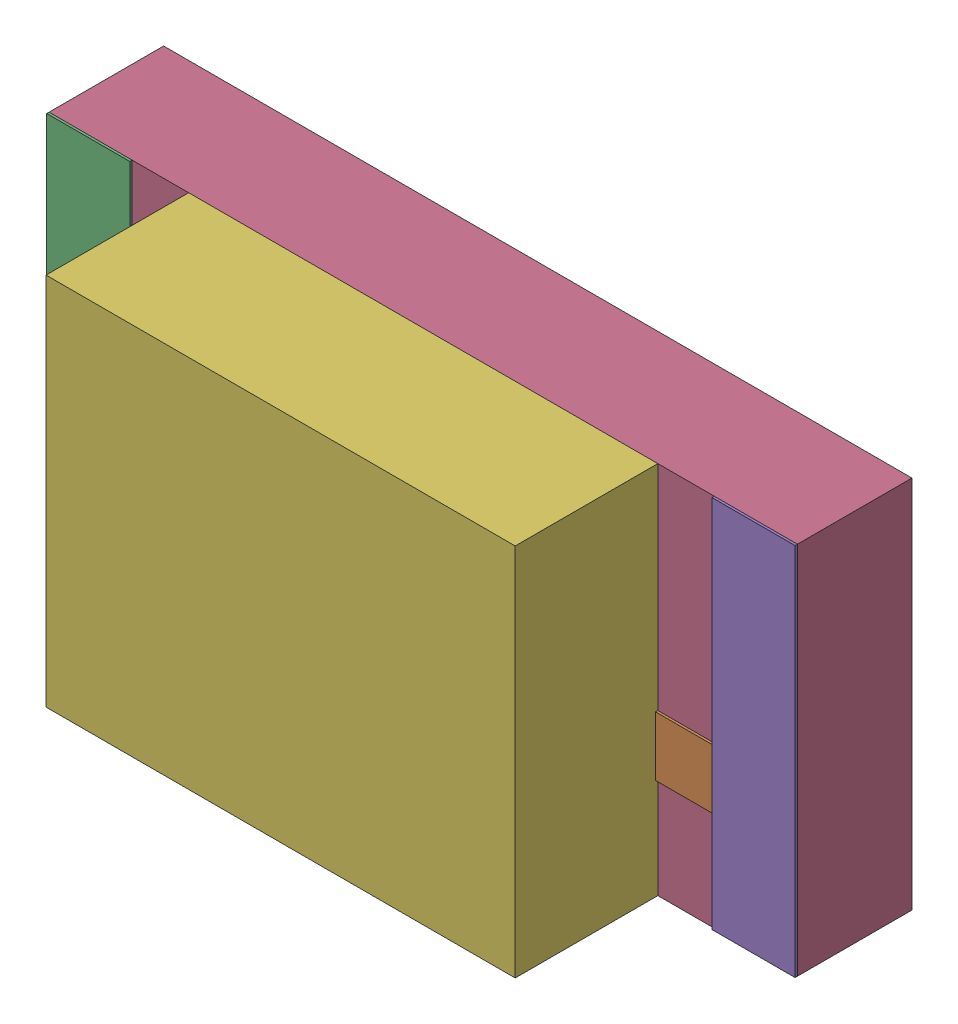
SolidWorks assembly SW3dPS-LED1206G, configuration Défaut. Lengths in mm.
Overall size (3.2 1.6 1.52).
14 component instances, 6 part files, 0 mates.
Components (placement in the parent):
- SW3dPS-LED1206G_Open_CASCADE_STEP_translator_6.2_262.2-1: SW3dPS-LED1206G_Open_CASCADE_STEP_translator_6.2_262.2 [Défaut] at origin size (3.2 1.6 1.1)
  - SW3dPS-LED1206G_352699472-1: SW3dPS-LED1206G_352699472 [Défaut] at (0.6096 0.0254 0.5027) size (0.65 0.76 0.01)
    - SW3dPS-LED1206G_Extruded-1: SW3dPS-LED1206G_Extruded [Défaut] at origin size (0.65 0.76 0.01)
  - SW3dPS-LED1206G_352698192-1: SW3dPS-LED1206G_352698192 [Défaut] at (2.1971 0.0254 0.5027) size (1.14 0.76 0.01)
    - SW3dPS-LED1206G_Extruded4-1: SW3dPS-LED1206G_Extruded4 [Défaut] at origin size (1.14 0.76 0.01)
  - SW3dPS-LED1206G_352697808-1: SW3dPS-LED1206G_352697808 [Défaut] at (0.1016 0.0127 0.5027) size (0.36 1.6 0.01)
    - SW3dPS-LED1206G_Extruded2-1: SW3dPS-LED1206G_Extruded2 [Défaut] at origin size (0.36 1.6 0.01)
  - SW3dPS-LED1206G_352697936-1: SW3dPS-LED1206G_352697936 [Défaut] at (1.524 0.0127 0.0127) size (3.2 1.6 0.49)
    - SW3dPS-LED1206G_Extruded1-1: SW3dPS-LED1206G_Extruded1 [Défaut] at origin size (3.2 1.6 0.49)
  - SW3dPS-LED1206G_352697808-2: SW3dPS-LED1206G_352697808 [Défaut] at (2.9464 0.0127 0.5027) size (0.36 1.6 0.01)
    - SW3dPS-LED1206G_Extruded2-1: SW3dPS-LED1206G_Extruded2 [Défaut] at origin size (0.36 1.6 0.01)
  - SW3dPS-LED1206G_352700880-1: SW3dPS-LED1206G_352700880 [Défaut] at (1.524 0.0127 0.5027) size (2.01 1.6 0.61)
    - SW3dPS-LED1206G_Extruded3-1: SW3dPS-LED1206G_Extruded3 [Défaut] at origin size (2.01 1.6 0.61)
- SW3dPS-LED1206G_Board-1: SW3dPS-LED1206G_Board [Défaut] at (0 0 -0.4039) size (0.03 0.03 0.42)
